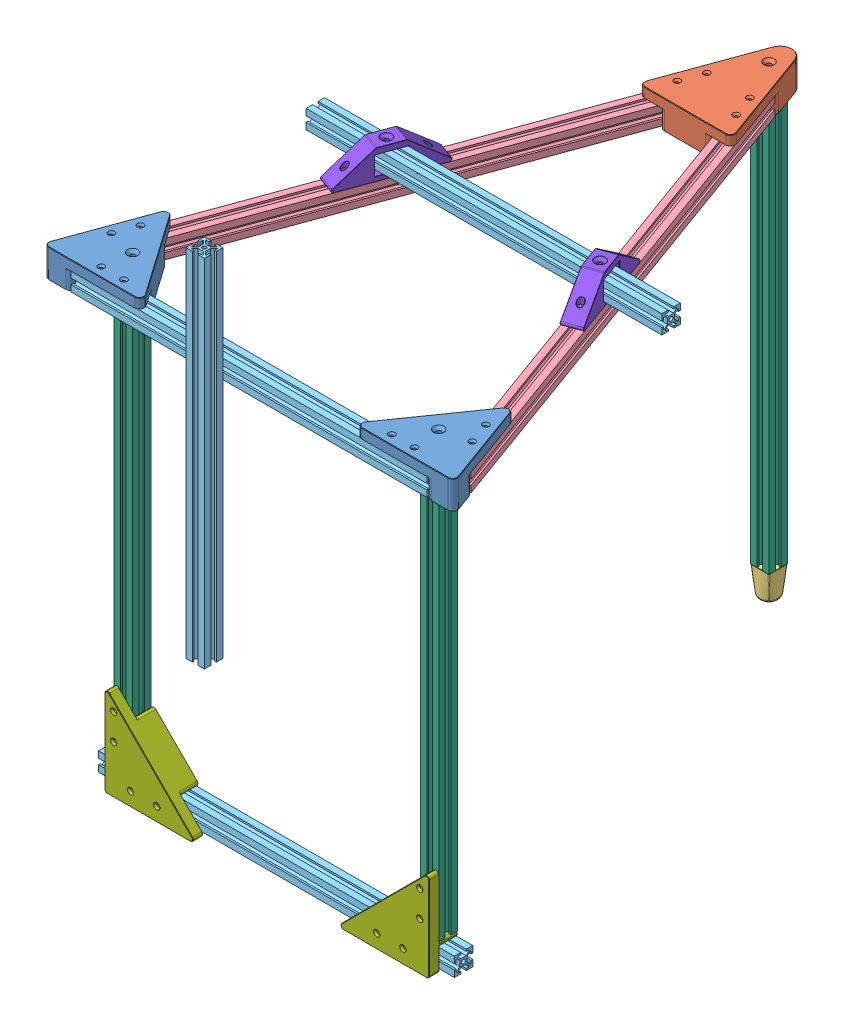
SolidWorks assembly DIP Tool A.2, configuration Left. Lengths in mm.
Overall size (443.68 632.03 649.77).
29 component instances, 13 part files, 76 mates.
Components (placement in the parent):
- HNKK5-3-1: HNKK5-3 [Predeterminado] at (-150 498 255.3902) x (0 0 1) z (1 0 0) size (15 3 10) (hidden)
- HNKK5-5-1: HNKK5-5 [Predeterminado] at (-5 497.4 330.9902) x (0 1 0) z (-1 0 0) size (15 3 10) (hidden)
- A3DIN7991 M3x16-3: A3DIN7991 M3x16 [Predeterminado] at (-155 510.5 262.8902) x (0.831098 0 0.556126) z (-0.556126 0 0.831098) size (5.98 16 5.98) (hidden)
- HNKK5-3-3: HNKK5-3 [Predeterminado] at (-17.5 512.9 5.4177) x (1 0 0) z (0 0 -1) size (15 3 10) (hidden)
- HNKK5-3-5: HNKK5-3 [Predeterminado] at (2.5 512.9 5.4177) x (1 0 0) z (0 0 -1) size (15 3 10) (hidden)
- A3DIN7991 M3x16-1: A3DIN7991 M3x16 [Predeterminado] at (-10 535.5 297.9902) size (5.98 16 5.98) (hidden)
- A3DIN7991 M3x16-2: A3DIN7991 M3x16 [Predeterminado] at (10 535.5 297.9902) size (5.98 16 5.98) (hidden)
- A3DIN7380 M5x30-1: A3DIN7380 M5x30 [Predeterminado] at (0 515 360.2402) x (0.996279 -0.086183 0) z (-0.086183 -0.996279 0) size (9.5 32.75 9.5) (hidden)
- A3DIN7991 M5x12-1: A3DIN7991 M5x12 [Predeterminado] at (-155 531.5 297.9902) size (9.78 12 9.78) (hidden)
- HNKK5-5-2: HNKK5-5 [Predeterminado] at (-147.5 512.9 302.9902) x (-1 0 0) z (0 0 1) size (15 3 10) (hidden)
- A3DIN7991 M3x16-6: A3DIN7991 M3x16 [Predeterminado] at (-154.9067 510.5 333.0543) x (0.831098 0 0.556126) z (-0.556126 0 0.831098) size (5.98 16 5.98) (hidden)
- HNKK5-3-7: HNKK5-3 [Predeterminado] at (-149.9067 498 325.5543) x (0 0 1) z (1 0 0) size (15 3 10) (hidden)
- Profile Mount A.1.1-1: Profile Mount A.1.1 [Main] at (-168.277 490 275.3167) size (103.25 30.5 97.63)
- Profile Mount A.1.1-2: Profile Mount A.1.1 [Main] at (204.4659 490 223.6336) x (-0.34202 0 -0.939693) z (0.939693 0 -0.34202) size (103.25 30.5 97.63)
- Profile Back Mount A.1-1: Profile Back Mount A.1 [Left] at (-25.6515 490 -267.655) x (-0.34202 0 0.939693) z (-0.939693 0 -0.34202) size (125.14 30.5 93)
- Profile Back Foot A.1-1: Profile Back Foot A.1 [Predeterminado] at (0 30 -288.1319) size (21.58 30.17 21.58)
- Profile 550-5: Profile 550 [Mecanitzat] at (-59.2354 480 -144.6839) x (0 -1 0) z (-0.34202 0 0.939693) size (20 20 550)
- Profile 550-6: Profile 550 [Mecanitzat] at (59.2354 480 -144.6839) x (0 -1 0) z (0.34202 0 0.939693) size (20 20 550)
- Side profile 385-3: Side profile 385 [Mecanitzat] at (-192.5 480 264.8167) x (0 -1 0) z (-1 0 0) size (20 20 385)
- Bottom profile 460-10: Bottom profile 460 [Mecanitzat] at (-165.6988 30 235) x (0 0 1) z (0 1 0) size (20 20 460)
- Bottom profile 460-11: Bottom profile 460 [Mecanitzat] at (165.6988 30 235) x (0 0 1) z (0 1 0) size (20 20 460)
- Bottom profile 460-12: Bottom profile 460 [Mecanitzat] at (0 30 -288.1319) x (0 0 1) z (0 1 0) size (20 20 460)
- Side profile 385-4: Side profile 385 [Mecanitzat] at (-192.5 15 235) x (0 -1 0) z (-1 0 0) size (20 20 385)
- Profile Stand A.2-1: Profile Stand A.2 [Left] at (-127.6988 6.5 245) x (1 0 0) z (0 -1 0) size (95.76 30.5 95.76)
- Profile Stand A.2-2: Profile Stand A.2 [Right] at (127.6988 6.5 245) x (1 0 0) z (0 -1 0) size (96 30.5 95.76)
- Sliding Mount A.1-1: Sliding Mount A.1 [Predeterminado] at (-115.6878 505 10.4177) x (0 -1 0) z (-0.939693 0 -0.34202) size (31.5 102.2 20)
- Sliding Mount A.1-4: Sliding Mount A.1 [Predeterminado] at (115.6878 505 10.4177) x (0 -1 0) z (0.939693 0 -0.34202) size (31.5 102.2 20)
- Side profile 385-2: Side profile 385 [Mecanitzat] at (192.5 504.9 10.4177) x (0 1 0) z (1 0 0) size (20 20 385)
- Side profile 385-1: Side profile 385 [Mecanitzat] at (0 246.8628 322.9902) x (1 0 0) z (0 -1 0) size (20 20 385)
Mates (geometry in assembly coordinates):
- Width5: width: plane of HNKK5-5-1 through (-5 498.4 329.3902) normal (-1 0 0); plane of HNKK5-5-1 through (5 498.4 329.3902) normal (1 0 0); plane of Side profile 385-1 through (-10 631.8628 325.9902) normal (-1 0 0); plane of Side profile 385-1 through (10 631.8628 325.9902) normal (1 0 0)
- Width6: width: plane of HNKK5-5-1 through (-4 512.4 329.3902) normal (0 1 0); plane of HNKK5-5-1 through (-4 497.4 329.3902) normal (0 -1 0); plane of Side profile 385-2 through (-192.5 514.9 13.4177) normal (0 1 0); plane of Side profile 385-2 through (-192.5 494.9 13.4177) normal (0 -1 0)
- Concentric39: concentric: cylinder of HNKK5-3-1 through (-155 498.001 262.8902) axis (0 -1 0) radius 1.25; cylinder of A3DIN7991 M3x16-3 through (-155 510.5 262.8902) axis (0 1 0) radius 1.5
- Coincident35: coincident: plane of Side profile 385-2 through (-192.5 512.9 7.4177) normal (0 -1 0); plane of HNKK5-3-3 through (-3.5 512.9 14.4177) normal (0 1 0)
- Width8: width: plane of HNKK5-3-3 through (-16.5 511.3 15.4177) normal (0 0 1); plane of HNKK5-3-3 through (-16.5 511.3 5.4177) normal (0 0 -1); plane of Side profile 385-2 through (-192.5 514.9 0.4177) normal (0 0 -1); plane of Side profile 385-2 through (-192.5 514.9 20.4177) normal (0 0 1)
- Concentric30: concentric: cylinder of ? through (-10 535.5 297.9902) axis (0 1 0) radius 1.6; cylinder of HNKK5-3-3 through (-10 523.001 297.9902) axis (0 -1 0) radius 1.25
- Coincident36: coincident: plane of Side profile 385-2 through (-192.5 512.9 7.4177) normal (0 -1 0); plane of HNKK5-3-5 through (16.5 512.9 14.4177) normal (0 1 0)
- Width9: width: plane of HNKK5-3-5 through (3.5 511.3 15.4177) normal (0 0 1); plane of HNKK5-3-5 through (3.5 511.3 5.4177) normal (0 0 -1); plane of Side profile 385-2 through (-192.5 514.9 0.4177) normal (0 0 -1); plane of Side profile 385-2 through (-192.5 514.9 20.4177) normal (0 0 1)
- Concentric31: concentric: cylinder of ? through (10 535.5 297.9902) axis (0 1 0) radius 1.6; cylinder of HNKK5-3-5 through (10 523.001 297.9902) axis (0 -1 0) radius 1.25
- Concentric32: concentric: cylinder of ? through (-10 535.5 297.9902) axis (0 1 0) radius 1.6; cylinder of A3DIN7991 M3x16-1 through (-10 535.5 297.9902) axis (0 1 0) radius 1.5
- Coincident37: coincident: plane of ? through (-155 535.5 242.9902) normal (0 1 0); plane of A3DIN7991 M3x16-1 through (-10 535.5 297.9902) normal (0 1 0)
- Concentric33: concentric: cylinder of A3DIN7991 M3x16-2 through (10 535.5 297.9902) axis (0 1 0) radius 1.5; cylinder of ? through (10 535.5 297.9902) axis (0 1 0) radius 1.6
- Coincident38: coincident: plane of A3DIN7991 M3x16-2 through (10 535.5 297.9902) normal (0 1 0); plane of ? through (-155 535.5 242.9902) normal (0 1 0)
- Coincident44: coincident: plane of Side profile 385-2 through (-192.5 512.9 7.4177) normal (0 -1 0); plane of HNKK5-5-2 through (-161.5 512.9 293.9902) normal (0 1 0)
- Concentric41: concentric: cylinder of A3DIN7991 M5x12-1 through (-155 531.5 297.9902) axis (0 1 0) radius 2.5; cylinder of HNKK5-5-2 through (-155 512.901 297.9902) axis (0 -1 0) radius 2.1
- Parallel18: parallel: plane of Side profile 385-2 through (-192.5 514.9 20.4177) normal (0 0 1); plane of HNKK5-5-2 through (-148.5 511.3 302.9902) normal (0 0 1)
- Concentric43: concentric: cylinder of A3DIN7991 M3x16-6 through (-154.9067 510.5 333.0543) axis (0 1 0) radius 1.5; cylinder of HNKK5-3-7 through (-154.9067 498.001 333.0543) axis (0 -1 0) radius 1.25
- Coincident55: coincident: plane of HNKK5-5-1 through (4 511.4 330.9902) normal (0 0 1); plane of Side profile 385-1 through (6 631.8628 330.9902) normal (0 0 -1)
- Concentric45: concentric: cylinder of A3DIN7380 M5x30-1 through (0 515 360.2402) axis (0 0 1) radius 2.5; cylinder of ? through (0 515 277.9892) axis (0 0 1) radius 2.65
- Distance5: distance = 0.5 mm: plane of A3DIN7380 M5x30-1 through (2.4907 514.7845 327.4902) normal (0 0 -1); plane of Side profile 385-1 through (-2.87 631.8628 326.9902) normal (0 0 1)
- Distancia1: distance = 0.25 mm: plane of ? through (-155 535.5 312.7402) normal (0 0 1); plane of Side profile 385-1 through (-3 631.8628 312.9902) normal (0 0 -1)
- Distancia2: distance = 0.25 mm: plane of Side profile 385-1 through (10 631.8628 312.9902) normal (1 0 0); plane of ? through (10.25 535.5 242.9902) normal (-1 0 0)
- Coincident58: coincident: plane of Profile Mount A.1.1-1 through (-168.277 490 275.3167) normal (0 -1 0); plane of Side profile 385-3 through (192.5 490 267.8167) normal (0 1 0)
- Coincident59: coincident: plane of Profile Mount A.1.1-1 through (-192.5 470 275.3167) normal (1 0 0); plane of Side profile 385-3 through (-192.5 480 264.8167) normal (-1 0 0)
- Coincident60: coincident: plane of Profile Mount A.1.1-1 through (-168.277 470 254.8167) normal (0 0 1); plane of Side profile 385-3 through (192.5 483 254.8167) normal (0 0 -1)
- Coincident61: coincident: plane of Profile Mount A.1.1-1 through (-168.277 490 275.3167) normal (0 -1 0); plane of Profile 550-5 through (-17.5919 490 -267.87) normal (0 1 0)
- Coincident62: coincident: plane of Profile Mount A.1.1-1 through (-164.1844 470 264.0724) normal (0.34202 0 -0.939693); plane of Profile 550-5 through (-202.8839 480 249.987) normal (-0.34202 0 0.939693)
- Coincident63: coincident: plane of Profile Mount A.1.1-1 through (-197.5796 470 264.6515) normal (-0.939693 0 -0.34202); plane of Profile 550-5 through (-5.3759 483 -263.4238) normal (0.939693 0 0.34202)
- Coincident64: coincident: plane of Side profile 385-3 through (192.5 480 264.8167) normal (1 0 0); plane of Profile Mount A.1.1-2 through (192.5 470 223.6336) normal (-1 0 0)
- Coincident65: coincident: plane of Side profile 385-3 through (192.5 490 254.8167) normal (0 1 0); plane of Profile Mount A.1.1-2 through (204.4659 490 223.6336) normal (0 -1 0)
- Coincident66: coincident: plane of Side profile 385-3 through (192.5 483 254.8167) normal (0 0 -1); plane of Profile Mount A.1.1-2 through (204.4659 470 254.8167) normal (0 0 1)
- Coincident67: coincident: plane of Profile Mount A.1.1-2 through (212.7507 470 246.3957) normal (-0.34202 0 -0.939693); plane of Profile 550-6 through (202.8839 480 249.987) normal (0.34202 0 0.939693)
- Coincident68: coincident: plane of Profile Mount A.1.1-2 through (185.2022 470 230.645) normal (0.939693 0 -0.34202); plane of Profile 550-6 through (5.3759 490 -263.4238) normal (-0.939693 0 0.34202)
- Coincident69: coincident: plane of Profile Mount A.1.1-2 through (204.4659 490 223.6336) normal (0 -1 0); plane of Profile 550-6 through (11.9537 490 -265.8179) normal (0 1 0)
- Coincident70: coincident: plane of Profile 550-5 through (0 286.4416 -291.6854) normal (0 1 0); plane of ? through (-27.5 286.4416 -285.054) normal (0 -1 0)
- Coincident71: coincident: plane of Profile 550-5; plane of ? through (-14.7726 271.4416 -307.0986) normal (-0.5 0 0.866025)
- Coincident72: coincident: plane of Profile 550-6; plane of ? through (-20.9516 271.4416 -277.113) normal (0.636213 0 0.771514)
- Coincident73: coincident: plane of Profile Mount A.1.1-1 through (-168.277 490 275.3167) normal (0 -1 0); plane of Bottom profile 460-10 through (-165.6988 490 235) normal (0 1 0)
- Concentric47: concentric: cylinder of Profile Mount A.1.1-1 through (-165.6988 500.5 235) axis (0 1 0) radius 2.65; cylinder of Bottom profile 460-10 through (-165.6988 30 235) axis (0 1 0) radius 2.1
- Parallel20: parallel: plane of Side profile 385-3 through (192.5 483 254.8167) normal (0 0 -1); plane of Bottom profile 460-10 through (-162.6988 30 245) normal (0 0 1)
- Coincident75: coincident: plane of Profile Mount A.1.1-2 through (204.4659 490 223.6336) normal (0 -1 0); plane of Bottom profile 460-11 through (165.6988 490 235) normal (0 1 0)
- Concentric48: concentric: cylinder of Profile Mount A.1.1-2 through (165.6988 500.5 235) axis (0 1 0) radius 2.65; cylinder of Bottom profile 460-11 through (165.6988 30 235) axis (0 1 0) radius 2.1
- Parallel21: parallel: plane of Side profile 385-3 through (192.5 483 254.8167) normal (0 0 -1); plane of Bottom profile 460-11 through (155.6988 30 245) normal (0 0 1)
- Symmetric1: symmetric: plane of Side profile 385-3 through (192.5 480 264.8167) normal (1 0 0); plane of Side profile 385-3 through (-192.5 480 264.8167) normal (-1 0 0); plane of assembly
- Coincident77: coincident: plane of Profile Back Mount A.1-1 through (-25.6515 490 -267.655) normal (0 -1 0); plane of Profile 550-5 through (-17.5919 490 -267.87) normal (0 1 0)
- Coincident78: coincident: plane of Profile Back Mount A.1-1 through (-25.6515 490 -267.655) normal (0 -1 0); plane of Profile 550-6 through (11.9537 490 -265.8179) normal (0 1 0)
- Coincident81: coincident: plane of Profile Back Mount A.1-1 through (0.3865 470 -277.132) normal (0.939693 0 -0.34202); plane of Profile 550-6 through (5.3759 477 -263.4238) normal (-0.939693 0 0.34202)
- Coincident82: coincident: plane of Profile Back Mount A.1-1 through (-6.3878 470 -260.6435) normal (-0.939693 0 -0.34202); plane of Profile 550-5 through (-5.3759 470 -263.4238) normal (0.939693 0 0.34202)
- Coincident83: coincident: plane of Profile Back Mount A.1-1 through (-25.6515 490 -267.655) normal (0 -1 0); plane of Bottom profile 460-12 through (0 490 -288.1319) normal (0 1 0)
- Concentric49: concentric: cylinder of Profile Back Mount A.1-1 through (0 500.5 -288.1319) axis (0 1 0) radius 2.65; cylinder of Bottom profile 460-12 through (0 30 -288.1319) axis (0 1 0) radius 2.1
- Parallel22: parallel: plane of Side profile 385-3 through (192.5 470 254.8167) normal (0 0 -1); plane of Bottom profile 460-12 through (3 30 -278.1319) normal (0 0 1)
- Coincident85: coincident: plane of ?; plane of assembly through (0 0 0) normal (1 0 0)
- Coincident86: coincident: plane of ? through (0 0 234.1569) normal (0 -1 0); plane of assembly through (0 0 0) normal (0 1 0)
- Coincident87: coincident: plane of Bottom profile 460-10 through (-168.6988 40.0286 224.1569) normal (0 0 -1); plane of ? through (-165 370.6055 224.1569) normal (0 0 -1)
- Symmetric2: symmetric: plane of Side profile 385-4 through (192.5 15 235) normal (1 0 0); plane of Side profile 385-4 through (-192.5 15 235) normal (-1 0 0); plane of assembly
- Coincident88: coincident: plane of Bottom profile 460-10 through (-162.6988 30 245) normal (0 0 1); plane of Profile Stand A.2-1 through (-127.6988 6.5 245) normal (0 0 -1)
- Coincident89: coincident: plane of Bottom profile 460-10 through (-155.6988 30 245) normal (1 0 0); plane of Profile Stand A.2-1 through (-155.6988 6.5 225) normal (-1 0 0)
- Coincident90: coincident: plane of Side profile 385-4 through (192.5 25 225) normal (0 1 0); plane of Profile Stand A.2-1 through (-127.6988 25 225) normal (0 -1 0)
- Coincident92: coincident: plane of Side profile 385-4 through (192.5 5 245) normal (0 0 1); plane of Profile Stand A.2-1 through (-127.6988 6.5 245) normal (0 0 -1)
- Coincident94: coincident: plane of Profile Stand A.2-1 through (-127.6988 0 255.5) normal (0 -1 0); plane of assembly through (0 0 0) normal (0 1 0)
- Coincident95: coincident: plane of Bottom profile 460-10 through (-165.6988 30 235) normal (0 -1 0); plane of Profile Stand A.2-1 through (-127.6988 30 225) normal (0 1 0)
- Coincident96: coincident: plane of Bottom profile 460-11 through (168.6988 30 245) normal (0 0 1); plane of Profile Stand A.2-2 through (127.6988 6.5 245) normal (0 0 -1)
- Coincident97: coincident: plane of Bottom profile 460-11 through (155.6988 30 238) normal (-1 0 0); plane of Profile Stand A.2-2 through (155.6988 6.5 225) normal (1 0 0)
- Coincident98: coincident: plane of Bottom profile 460-11 through (165.6988 30 235) normal (0 -1 0); plane of Profile Stand A.2-2 through (127.6988 30 225) normal (0 1 0)
- Coincident99: coincident: plane of Profile 550-5 through (-17.5919 490 -267.87) normal (0 1 0); plane of Sliding Mount A.1-1 through (-106.2909 490 13.8379) normal (0 -1 0)
- Width10: width: plane of Sliding Mount A.1-1 through (-106.2909 505 13.8379) normal (0.939693 0 0.34202); plane of Sliding Mount A.1-1 through (-125.0848 505 6.9975) normal (-0.939693 0 -0.34202); plane of Profile 550-5 through (-24.1697 490 -270.2642) normal (-0.939693 0 -0.34202); plane of Profile 550-5 through (-5.3759 483 -263.4238) normal (0.939693 0 0.34202)
- Distance6: distance = 225 mm: plane of assembly through (0 0 0) normal (0 0 1); plane of Side profile 385-4 through (192.5 5 225) normal (0 0 -1)
- Coincident101: coincident: plane of Profile 550-6 through (24.1697 490 -270.2642) normal (0 1 0); plane of Sliding Mount A.1-4 through (106.2909 490 13.8379) normal (0 -1 0)
- Width13: width: plane of Sliding Mount A.1-4 through (125.0848 505 6.9975) normal (0.939693 0 -0.34202); plane of Sliding Mount A.1-4 through (106.2909 505 13.8379) normal (-0.939693 0 0.34202); plane of Profile 550-6 through (5.3759 490 -263.4238) normal (-0.939693 0 0.34202); plane of Profile 550-6 through (24.1697 483 -270.2642) normal (0.939693 0 -0.34202)
- Width15: width: plane of Sliding Mount A.1-4 through (130.6878 494.9 20.5177) normal (0 0 -1); plane of Sliding Mount A.1-4 through (130.6878 494.9 0.3177) normal (0 0 1); plane of Side profile 385-2 through (-192.5 514.9 20.4177) normal (0 0 1); plane of Side profile 385-2 through (-192.5 514.9 0.4177) normal (0 0 -1)
- Coincident104: coincident: plane of Sliding Mount A.1-1 through (-106.2909 494.9 13.8379) normal (0 1 0); plane of Side profile 385-2 through (-192.5 494.9 0.4177) normal (0 -1 0)
- Width14: width: plane of Side profile 385-2 through (-192.5 514.9 20.4177) normal (0 0 1); plane of Side profile 385-2 through (-192.5 514.9 0.4177) normal (0 0 -1); plane of Sliding Mount A.1-1 through (-100.6878 494.9 20.5177) normal (0 0 -1); plane of Sliding Mount A.1-1 through (-100.6878 494.9 0.3177) normal (0 0 1)
- Symmetric3: symmetric: plane of Side profile 385-2 through (192.5 504.9 10.4177) normal (1 0 0); plane of Side profile 385-2 through (-192.5 504.9 10.4177) normal (-1 0 0); plane of assembly
- Concentric50: concentric: cylinder of Bottom profile 460-12 through (0 30 -288.1319) axis (0 1 0) radius 2.1; cylinder of Profile Back Foot A.1-1 through (0 0 -288.1319) axis (0 -1 0) radius 2.75
- Coincident105: coincident: plane of Bottom profile 460-12 through (0 30 -288.1319) normal (0 -1 0); plane of Profile Back Foot A.1-1 through (0 30 -288.1319) normal (0 1 0)
- Parallel24: parallel: plane of Bottom profile 460-12 through (-3 30 -298.1319) normal (0 0 -1); plane of Profile Back Foot A.1-1 through (0 30 -288.1319) normal (0 0 1)
